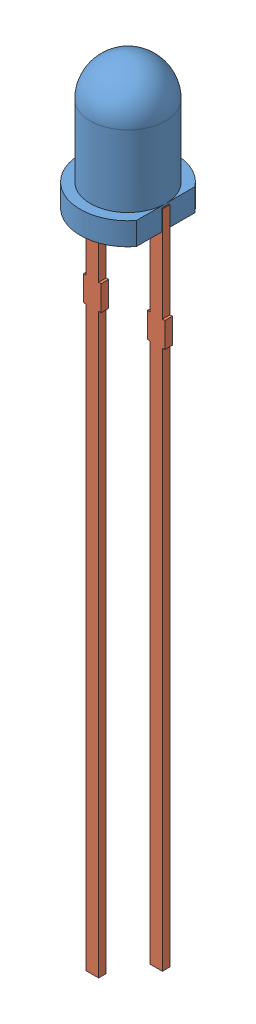
SolidWorks assembly LED short, configuration Default. Lengths in mm.
Overall size (3.52 32.25 3.8).
2 component instances, 2 part files, 2 mates.
Components (placement in the parent):
- LED Head-1: LED Head [3mm Blue] at origin size (3.4 5.25 3.8)
- LED Leads-1: LED Leads [3mm long] at (0 -1.408 0) size (3.24 28.29 0.3)
Mates (geometry in assembly coordinates):
- Coincident1: coincident: line of LED Head-1 through (0 2.85 0) axis (0 -1 0); point of LED Leads-1
- Distance1: distance = 3 mm anti-aligned: plane of LED Leads-1 through (1.62 -3.9 0.15) normal (0 1 0); plane of LED Head-1 through (0 -0.9 0) normal (0 -1 0)
